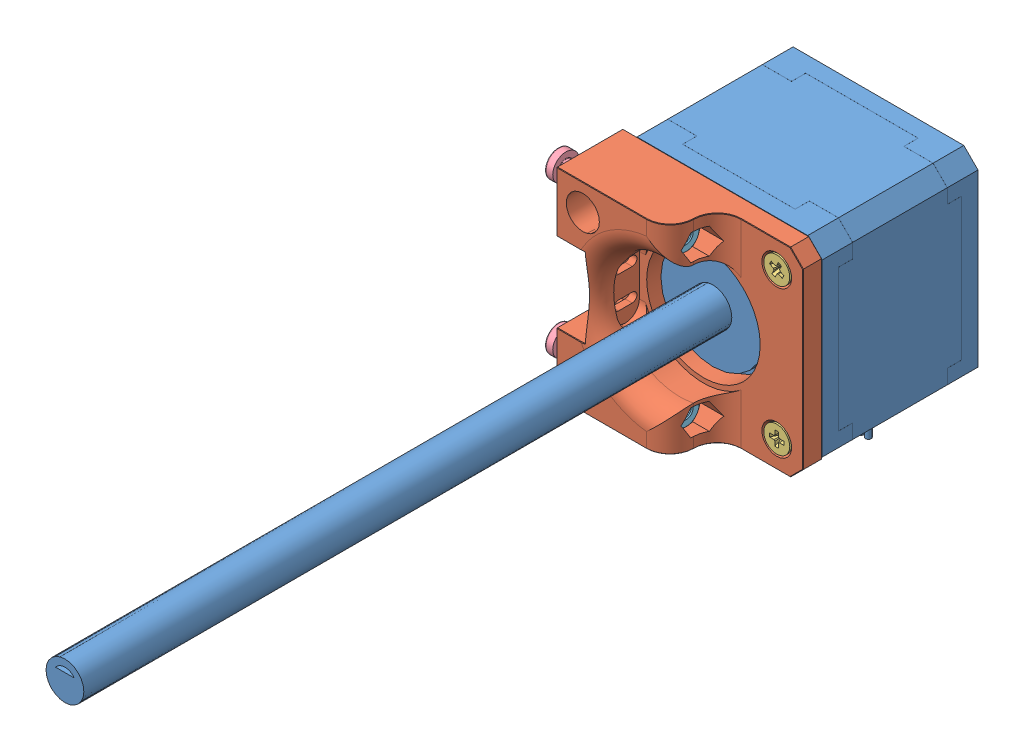
SolidWorks assembly Zmotor2, configuration Default. Lengths in mm.
Overall size (48.45 59.12 172).
10 component instances, 5 part files, 12 mates.
Components (placement in the parent):
- Steper Motor 34mm (42HD0401-135L)-1: Steper Motor 34mm (42HD0401-135L) [Default] at origin size (42.1 59.12 172)
- Z Motor mount-1: Z Motor mount [Valor predeterminado] at (-330.7157 -87.3227 33) x (0 1 0) z (0 0 1) size (42.1 42.1 15.64)
- ISO 7046-1 - M3 x 10 - Z --- 10N-1: ISO 7046-1 - M3 x 10 - Z --- 10N [ISO 7046-1 - M3 x 12 - Z --- 12N] at (-15.5 15.5 37) x (0 0 -1) z (0.999999 0.001551 0) size (12 5.5 5.5)
- ISO 7046-1 - M3 x 10 - Z --- 10N-2: ISO 7046-1 - M3 x 10 - Z --- 10N [ISO 7046-1 - M3 x 12 - Z --- 12N] at (15.5 15.5 37) x (0 0 -1) z (0.444535 0.895762 0) size (12 5.5 5.5)
- ISO 7046-1 - M3 x 10 - Z --- 10N-3: ISO 7046-1 - M3 x 10 - Z --- 10N [ISO 7046-1 - M3 x 12 - Z --- 12N] at (15.5 -15.5 37) x (0 0 -1) z (0.999915 -0.013072 0) size (12 5.5 5.5)
- ISO 7046-1 - M3 x 10 - Z --- 10N-4: ISO 7046-1 - M3 x 10 - Z --- 10N [ISO 7046-1 - M3 x 12 - Z --- 12N] at (-15.5 -15.5 37) x (0 0 -1) z (0.999885 0.015174 0) size (12 5.5 5.5)
- ISO 7045 - M3 x 20 - Z --- 20N-3: ISO 7045 - M3 x 20 - Z --- 20N [ISO 7045 - M3 x 25 - Z --- 25N] at (-27.45 -16.0364 41.0127) x (1 0 0) z (0 -1 0) size (27.35 5.6 5.6)
- ISO 7045 - M3 x 20 - Z --- 20N-4: ISO 7045 - M3 x 20 - Z --- 20N [ISO 7045 - M3 x 25 - Z --- 25N] at (-27.45 16.0364 41.0127) x (1 0 0) z (0 -1 0) size (27.35 5.6 5.6)
- hex thin nut chamfered gradeab_iso-1: hex thin nut chamfered gradeab_iso [Hexagon Thin Nut ISO - 4035 - M3 - N] at (0.35 16.0364 41.0127) x (0 1 0) z (1 0 0) size (5.5 6.35 1.8)
- hex thin nut chamfered gradeab_iso-2: hex thin nut chamfered gradeab_iso [Hexagon Thin Nut ISO - 4035 - M3 - N] at (0.35 -16.0364 41.0127) x (0 1 0) z (1 0 0) size (5.5 6.35 1.8)
Mates (geometry in assembly coordinates):
- Coincidente255: coincident: plane of Steper Motor 34mm (42HD0401-135L)-1 through (21.05 21.05 33) normal (0 0 1); plane of Z Motor mount-1 through (-330.7157 -87.3227 33) normal (0 0 -1)
- Coincidente256: coincident: plane of Steper Motor 34mm (42HD0401-135L)-1 through (-21.05 21.05 33) normal (0 1 0); plane of Z Motor mount-1 through (21.05 21.05 37) normal (0 1 0)
- Coincidente258: coincident: plane of Steper Motor 34mm (42HD0401-135L)-1 through (21.05 -21.05 33) normal (1 0 0); plane of Z Motor mount-1 through (21.05 21.05 37) normal (1 0 0)
- Coincidente259: coincident: cone of Z Motor mount-1 through (-15.5 15.5 37) axis (0 0 -1); cone of ISO 7046-1 - M3 x 10 - Z --- 10N-1 through (-15.5 15.5 36.6) axis (0 0 -1)
- Coincidente260: coincident: cone of Z Motor mount-1 through (15.5 15.5 37) axis (0 0 -1); cone of ISO 7046-1 - M3 x 10 - Z --- 10N-2 through (15.5 15.5 36.6) axis (0 0 -1)
- Coincidente261: coincident: cone of Z Motor mount-1 through (15.5 -15.5 37) axis (0 0 -1); cone of ISO 7046-1 - M3 x 10 - Z --- 10N-3 through (15.5 -15.5 36.6) axis (0 0 -1)
- Coincidente262: coincident: cone of Z Motor mount-1 through (-15.5 -15.5 37) axis (0 0 -1); cone of ISO 7046-1 - M3 x 10 - Z --- 10N-4 through (-15.5 -15.5 36.6) axis (0 0 -1)
- Concentric45: concentric: cylinder of Z Motor mount-1 through (-21.05 16.0364 41.0127) axis (-1 0 0) radius 1.6; cylinder of hex thin nut chamfered gradeab_iso-1 through (-24.6875 16.0364 41.0127) axis (1 0 0) radius 1.5
- Coincident786995: coincident: plane of Z Motor mount-1 through (-1.45 -87.3227 33) normal (1 0 0); plane of hex thin nut chamfered gradeab_iso-1 through (-1.45 16.0364 44.1881) normal (-1 0 0)
- Concentric46: concentric: cylinder of Z Motor mount-1 through (-21.05 -16.0364 41.0127) axis (-1 0 0) radius 1.6; cylinder of hex thin nut chamfered gradeab_iso-2 through (-24.6875 -16.0364 41.0127) axis (1 0 0) radius 1.5
- Coincident786996: coincident: plane of Z Motor mount-1 through (-1.45 -87.3227 33) normal (1 0 0); plane of hex thin nut chamfered gradeab_iso-2 through (-1.45 -16.0364 44.1881) normal (-1 0 0)
- Concentric56: concentric: cylinder of Z Motor mount-1 through (-21.05 16.0364 41.0127) axis (-1 0 0) radius 1.6; cylinder of ISO 7045 - M3 x 20 - Z --- 20N-4 through (-52.85 16.0364 41.0127) axis (-1 0 0) radius 1.5
